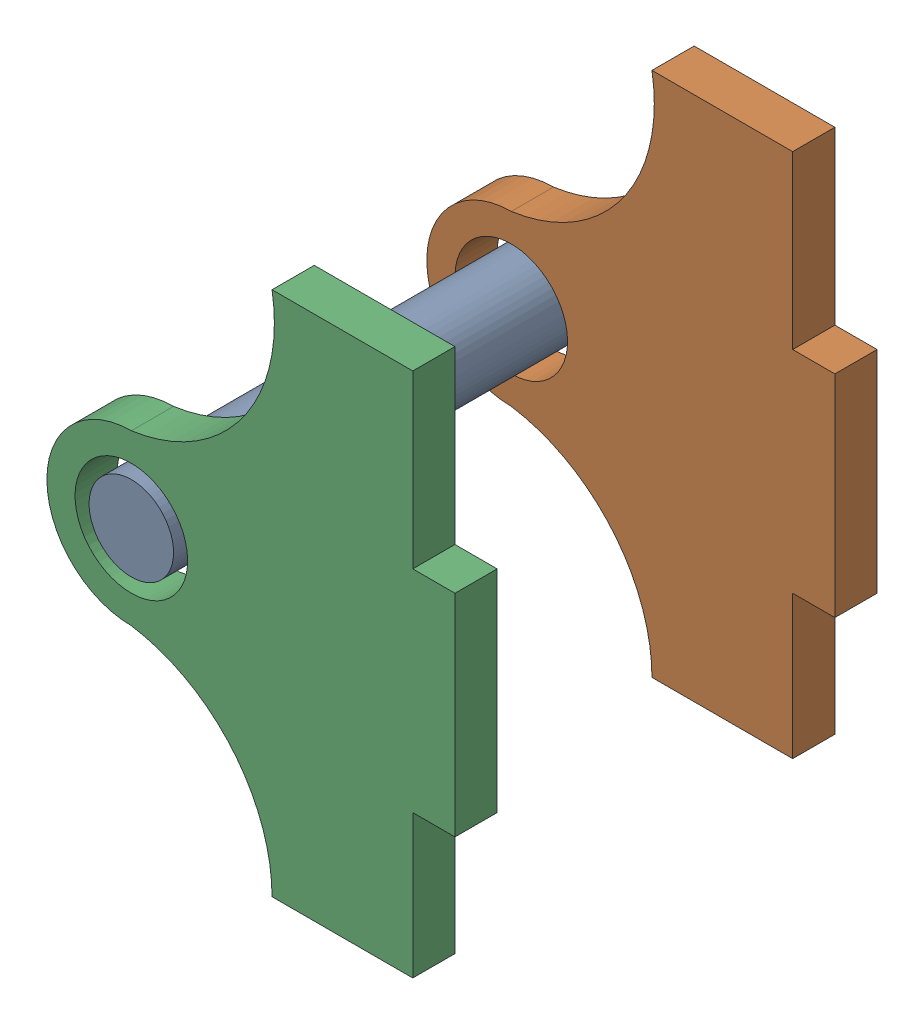
SolidWorks assembly cW robe assem, configuration Default. Lengths in mm.
Overall size (29 37.36 30).
3 component instances, 2 part files, 4 mates.
Components (placement in the parent):
- rode bully-1: rode bully [Default] at (-207.987 34.4528 146.1546) size (6 6 30)
- bully support-1: bully support [Default] at (-207.987 34.4528 149.1546) x (0 -1 0) z (0 0 -1) size (37.36 29 3)
- bully support-2: bully support [Default] at (-207.987 34.4528 176.1546) x (0 -1 0) z (0 0 -1) size (37.36 29 3)
Mates (geometry in assembly coordinates):
- Concentric2: concentric anti-aligned: cylinder of rode bully-1 through (-207.987 34.4528 176.1546) axis (0 0 -1) radius 3; cylinder of bully support-2 through (-207.987 34.4528 173.1546) axis (0 0 1) radius 4
- Concentric3: concentric anti-aligned: cylinder of rode bully-1 through (-207.987 34.4528 176.1546) axis (0 0 -1) radius 3; cylinder of bully support-1 through (-207.987 34.4528 146.1546) axis (0 0 1) radius 4
- Distance1: distance = 0 mm aligned: plane of bully support-2 through (-209.6431 52.1585 176.1546) normal (0 0 1); plane of rode bully-1 through (-207.987 34.4528 176.1546) normal (0 0 1)
- Distance2: distance = 0 mm aligned: plane of bully support-1 through (-209.6431 52.1585 146.1546) normal (0 0 -1); plane of rode bully-1 through (-207.987 34.4528 146.1546) normal (0 0 -1)
